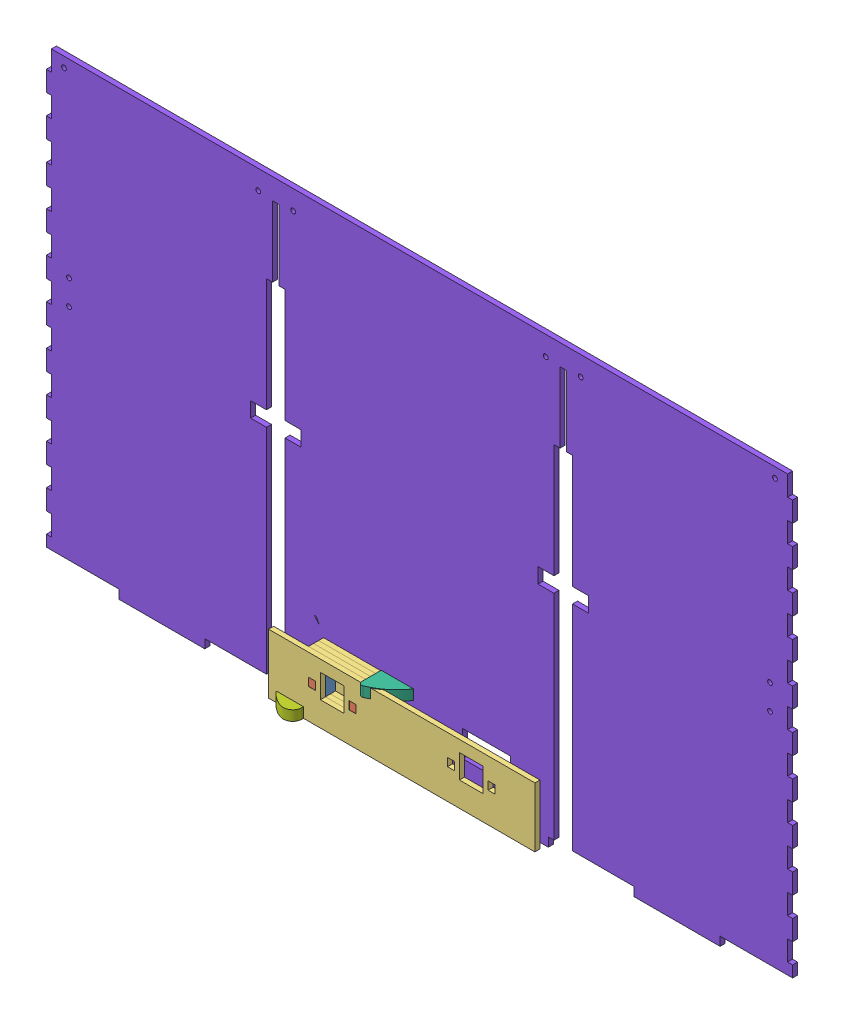
SolidWorks assembly extended nosepoke, configuration Default. Lengths in mm.
Overall size (470.79 279.4 46.18).
26 component instances, 8 part files, 60 mates.
Components (placement in the parent):
- inner floor-1: inner floor [Default] at (-20.7659 5.8025 34.2831) size (3.17 16.5 43)
- preferenceV2_dispenser_IRAssembly - Copy-2: preferenceV2_dispenser_IRAssembly - Copy [Default] at (-26.7909 7.3575 22.0081) x (1 0 0) z (0 -1 0) size (30.1 15.2 5)
  - sparkfunIR_LEDandCase-1: sparkfunIR_LEDandCase [2Pin] at (-11.0025 21.2786 44.4241) x (-1 0 0) z (0 0 -1) size (4.3 15.2 5)
    - sparkfunIR_casing-1: sparkfunIR_casing [Default] at (-40.6525 -5.8286 32.4491) x (1 0 0) z (0 0 -1) size (4.3 15.2 5)
  - sparkfunIR_LEDandCase-2: sparkfunIR_LEDandCase [3Pin] at (44.5025 21.2786 -20.4741) size (4.3 15.2 5)
    - sparkfunIR_casing-1: sparkfunIR_casing [Default] at (-40.6525 -5.8286 32.4491) x (1 0 0) z (0 0 -1) size (4.3 15.2 5)
- outside guard extended-1: outside guard extended [Default] at (9.7924 23.2146 37.4581) size (168 37.72 3.17)
- inner floor-2: inner floor [Default] at (-2.5909 5.8025 34.2831) size (3.17 16.5 43)
- outside guard extended-3: outside guard extended [second face] at (9.7974 23.2146 34.2831) size (36.35 37.72 3.17)
- outside guard extended-4: outside guard extended [second face] at (9.7974 23.2146 31.1081) size (36.35 37.72 3.17)
- outside guard extended-5: outside guard extended [back face] at (9.7974 23.2146 27.9331) size (36.35 37.72 3.17)
- nosepoke_cap-1: nosepoke_cap [Default] at (-25.7319 2.2657 -1.4169) size (36.45 15.97 23) (hidden)
- Part2^extended nosepoke-1: Part2^extended nosepoke [Default] at (9.7924 26.7946 21.5831) size (51.28 36.05 3.17) (hidden, virtual)
- side_guard_A-1: side_guard_A [Default] at (8.0751 11.9085 24.7581) x (1 0 0) z (0 0 -1) size (20.32 6.35 14.38) (hidden)
- side_guard_A-2: side_guard_A [Default] at (8.0751 5.5585 24.7581) x (1 0 0) z (0 0 -1) size (20.32 6.35 14.38) (hidden)
- side_guard_A-3: side_guard_A [Default] at (8.0751 -19.8415 24.7581) x (1 0 0) z (0 0 -1) size (20.32 6.35 14.38) (hidden)
- side_guard_A-4: side_guard_A [Default] at (8.0751 -0.7915 24.7581) x (1 0 0) z (0 0 -1) size (20.32 6.35 14.38) (hidden)
- side_guard_A-5: side_guard_A [Default] at (8.0751 -7.1415 24.7581) x (1 0 0) z (0 0 -1) size (20.32 6.35 14.38) (hidden)
- side_guard_A-6: side_guard_A [Default] at (8.0751 -13.4915 24.7581) x (1 0 0) z (0 0 -1) size (20.32 6.35 14.38) (hidden)
- side_guard_B-1: side_guard_B [Default] at (-49.4865 -19.8415 24.7581) x (1 0 0) z (0 0 -1) size (23.13 6.35 20.07) (hidden)
- side_guard_B-2: side_guard_B [Default] at (-49.4865 -0.7915 24.7581) x (1 0 0) z (0 0 -1) size (23.13 6.35 20.07) (hidden)
- side_guard_B-3: side_guard_B [Default] at (-49.4865 -7.1415 24.7581) x (1 0 0) z (0 0 -1) size (23.13 6.35 20.07) (hidden)
- side_guard_B-4: side_guard_B [Default] at (-49.4865 5.5585 24.7581) x (1 0 0) z (0 0 -1) size (23.13 6.35 20.07) (hidden)
- side_guard_B-5: side_guard_B [Default] at (-49.4865 11.9085 24.7581) x (1 0 0) z (0 0 -1) size (23.13 6.35 20.07) (hidden)
- side_guard_B-6: side_guard_B [Default] at (-49.4865 -13.4915 24.7581) x (1 0 0) z (0 0 -1) size (23.13 6.35 20.07) (hidden)
- preferenceV2_chamberFront_nosepokes_scoped-1: preferenceV2_chamberFront_nosepokes_scoped [front_nosepoke_scoped] at (32.2189 107.6367 21.5831) size (470.79 279.4 3.17)
Mates (geometry in assembly coordinates):
- Coincident35: coincident aligned: plane of outside guard extended-1 through (-28.2709 11.5258 -2.2013) normal (0 1 0); plane of outside guard extended-3 through (-28.2659 11.5258 -5.3763) normal (0 1 0)
- Coincident37: coincident aligned: plane of outside guard extended-3 through (-28.2659 11.5258 -5.3763) normal (0 1 0); plane of outside guard extended-4 through (-28.2659 11.5258 -8.5513) normal (0 1 0)
- Coincident38: coincident aligned: plane of outside guard extended-4 through (-28.2659 11.5258 -8.5513) normal (0 1 0); plane of outside guard extended-5 through (-28.2659 11.5258 -11.7263) normal (0 1 0)
- Coincident39: coincident aligned: plane of outside guard extended-4 through (8.0801 8.3508 27.9331) normal (1 0 0); plane of outside guard extended-5 through (8.0801 8.3508 24.7581) normal (1 0 0)
- Coincident40: coincident aligned: plane of outside guard extended-3 through (8.0801 8.3508 31.1081) normal (1 0 0); plane of outside guard extended-4 through (8.0801 8.3508 27.9331) normal (1 0 0)
- Coincident41: coincident: plane of outside guard extended-3 through (-25.0909 -10.6975 24.2831) normal (1 0 0); plane of outside guard extended-4 through (-25.0909 -10.6975 21.1081) normal (1 0 0)
- Coincident42: coincident: plane of outside guard extended-4 through (-25.0909 -10.6975 21.1081) normal (1 0 0); plane of outside guard extended-5 through (-25.0909 -10.6975 17.9331) normal (1 0 0)
- Coincident44: coincident: plane of outside guard extended-1 through (-25.0909 -5.6175 34.2831) normal (1 0 0); plane of outside guard extended-3 through (-25.0909 -10.6975 24.2831) normal (1 0 0)
- Coincident45: coincident: plane of outside guard extended-3 through (-25.0909 -10.6975 24.2831) normal (1 0 0); plane of outside guard extended-4 through (-25.0909 -10.6975 21.1081) normal (1 0 0)
- Coincident46: coincident: plane of outside guard extended-4 through (-25.0909 -10.6975 21.1081) normal (1 0 0); plane of outside guard extended-5 through (-25.0909 -10.6975 17.9331) normal (1 0 0)
- Coincident50: coincident anti-aligned: plane of outside guard extended-1 through (9.7924 23.2146 34.2831) normal (0 0 -1); plane of outside guard extended-3 through (9.7974 23.2146 34.2831) normal (0 0 1)
- Coincident51: coincident anti-aligned: plane of outside guard extended-3 through (9.7974 23.2146 31.1081) normal (0 0 -1); plane of outside guard extended-4 through (9.7974 23.2146 31.1081) normal (0 0 1)
- Coincident52: coincident anti-aligned: plane of outside guard extended-4 through (9.7974 23.2146 27.9331) normal (0 0 -1); plane of outside guard extended-5 through (9.7974 23.2146 27.9331) normal (0 0 1)
- Coincident53: coincident anti-aligned: plane of inner floor-1 through (-17.5909 5.8025 34.2831) normal (0 0 1); plane of outside guard extended-1 through (9.7924 23.2146 34.2831) normal (0 0 -1)
- Coincident55: coincident: plane of inner floor-1 through (-17.5909 -10.6975 34.2831) normal (0 -1 0); plane of outside guard extended-5 through (-28.2659 -10.6975 -11.7263) normal (0 1 0)
- Coincident56: coincident anti-aligned: plane of outside guard extended-1 through (9.7924 23.2146 34.2831) normal (0 0 -1); plane of inner floor-2 through (0.5841 5.8025 34.2831) normal (0 0 1)
- Coincident57: coincident: plane of inner floor-2 through (0.5841 -10.6975 34.2831) normal (0 -1 0); plane of outside guard extended-5 through (-28.2659 -10.6975 -11.7263) normal (0 1 0)
- Coincident59: coincident aligned: plane of preferenceV2_dispenser_IRAssembly - Copy-2/sparkfunIR_LEDandCase-1/sparkfunIR_casing-1 through (5.0091 -7.1175 37.4581) normal (0 0 1); plane of outside guard extended-1 through (9.7924 23.2146 37.4581) normal (0 0 1)
- Coincident60: coincident: plane of inner floor-2 through (-2.5909 5.8025 34.2831) normal (-1 0 0); plane of outside guard extended-5 through (-2.5909 4.3025 24.7581) normal (1 0 0)
- Coincident61: coincident: plane of inner floor-1 through (-17.5909 5.8025 34.2831) normal (1 0 0); plane of outside guard extended-5 through (-17.5909 4.3025 24.7581) normal (-1 0 0)
- Distance2: distance = 3.175 mm anti-aligned: plane of nosepoke_cap-1 through (-25.7319 2.2657 21.5831) normal (0 0 1); plane of outside guard extended-5 through (9.7974 23.2146 24.7581) normal (0 0 -1)
- Coincident67: coincident anti-aligned: plane of inner floor-2 through (0.5841 5.8025 34.2831) normal (0 1 0); plane of nosepoke_cap-1 through (-2.5909 5.8025 -19.2169) normal (0 -1 0)
- Coincident68: coincident anti-aligned: plane of inner floor-2 through (-2.5909 5.8025 34.2831) normal (-1 0 0); plane of nosepoke_cap-1 through (-2.5909 5.8025 -19.2169) normal (1 0 0)
- Coincident72: coincident anti-aligned: plane of outside guard extended-5 through (9.7974 23.2146 24.7581) normal (0 0 -1); plane of Part2^extended nosepoke-1 through (9.7924 26.7946 24.7581) normal (0 0 1)
- Coincident73: coincident anti-aligned: plane of preferenceV2_dispenser_IRAssembly - Copy-2/sparkfunIR_LEDandCase-2/sparkfunIR_casing-1 through (-22.9409 -7.1175 37.4581) normal (0 -1 0); plane of Part2^extended nosepoke-1 through (-25.0909 -7.1175 24.7581) normal (0 1 0)
- Coincident74: coincident anti-aligned: plane of preferenceV2_dispenser_IRAssembly - Copy-2/sparkfunIR_LEDandCase-2/sparkfunIR_casing-1 through (-25.0909 -2.1175 37.4581) normal (-1 0 0); plane of Part2^extended nosepoke-1 through (-25.0909 -7.1175 24.7581) normal (1 0 0)
- Coincident94: coincident aligned: plane of outside guard extended-5 through (9.7974 23.2146 24.7581) normal (0 0 -1); plane of side_guard_A-3 through (8.0751 -26.1915 24.7581) normal (0 0 -1)
- Coincident95: coincident aligned: plane of outside guard extended-1 through (-28.2709 -26.1915 -4.0938) normal (0 -1 0); plane of side_guard_A-3 through (-3.9794 -26.1915 2.7588) normal (0 -1 0)
- Coincident96: coincident: plane of outside guard extended-1 through (8.0751 8.3508 34.2831) normal (1 0 0); plane of side_guard_A-3 through (8.0751 -26.1915 24.7581) normal (-1 0 0)
- Coincident97: coincident anti-aligned: plane of side_guard_A-3 through (-3.9794 -19.8415 2.7588) normal (0 1 0); plane of side_guard_A-6 through (-3.9794 -19.8415 2.7588) normal (0 -1 0)
- Concentric7: concentric aligned: cylinder of side_guard_A-3 through (-3.9794 -26.1915 2.7588) axis (0 1 0) radius 39.1418; cylinder of side_guard_A-6 through (-3.9794 -19.8415 2.7588) axis (0 1 0) radius 39.1418
- Coincident98: coincident anti-aligned: plane of side_guard_A-5 through (-3.9794 -13.4915 2.7588) normal (0 -1 0); plane of side_guard_A-6 through (-3.9794 -13.4915 2.7588) normal (0 1 0)
- Concentric8: concentric aligned: cylinder of side_guard_A-5 through (-3.9794 -13.4915 2.7588) axis (0 1 0) radius 39.1418; cylinder of side_guard_A-6 through (-3.9794 -19.8415 2.7588) axis (0 1 0) radius 39.1418
- Coincident99: coincident anti-aligned: plane of side_guard_A-4 through (-3.9794 -7.1415 2.7588) normal (0 -1 0); plane of side_guard_A-5 through (-3.9794 -7.1415 2.7588) normal (0 1 0)
- Concentric9: concentric aligned: cylinder of side_guard_A-4 through (-3.9794 -7.1415 2.7588) axis (0 1 0) radius 39.1418; cylinder of side_guard_A-5 through (-3.9794 -13.4915 2.7588) axis (0 1 0) radius 39.1418
- Coincident100: coincident anti-aligned: plane of side_guard_A-2 through (-3.9794 -0.7915 2.7588) normal (0 -1 0); plane of side_guard_A-4 through (-3.9794 -0.7915 2.7588) normal (0 1 0)
- Coincident101: coincident anti-aligned: plane of side_guard_A-2 through (-3.9794 -0.7915 2.7588) normal (0 -1 0); plane of side_guard_A-4 through (-3.9794 -0.7915 2.7588) normal (0 1 0)
- Concentric10: concentric aligned: cylinder of side_guard_A-2 through (-3.9794 -0.7915 2.7588) axis (0 1 0) radius 39.1418; cylinder of side_guard_A-4 through (-3.9794 -7.1415 2.7588) axis (0 1 0) radius 39.1418
- Coincident102: coincident anti-aligned: plane of side_guard_A-1 through (-3.9794 5.5585 2.7588) normal (0 -1 0); plane of side_guard_A-2 through (-3.9794 5.5585 2.7588) normal (0 1 0)
- Concentric11: concentric aligned: cylinder of side_guard_A-1 through (-3.9794 5.5585 2.7588) axis (0 1 0) radius 39.1418; cylinder of side_guard_A-2 through (-3.9794 -0.7915 2.7588) axis (0 1 0) radius 39.1418
- Coincident103: coincident anti-aligned: plane of outside guard extended-4 through (-28.2659 8.3508 27.9331) normal (-1 0 0); plane of side_guard_B-1 through (-28.2659 -26.1915 24.7581) normal (1 0 0)
- Coincident104: coincident aligned: plane of outside guard extended-5 through (9.7974 23.2146 24.7581) normal (0 0 -1); plane of side_guard_B-1 through (-49.4865 -26.1915 24.7581) normal (0 0 -1)
- Coincident105: coincident aligned: plane of outside guard extended-5 through (-28.2659 -26.1915 -13.6188) normal (0 -1 0); plane of side_guard_B-1 through (-42.4162 -26.1915 40.4723) normal (0 -1 0)
- Coincident106: coincident anti-aligned: plane of side_guard_B-1 through (-42.4162 -19.8415 40.4723) normal (0 1 0); plane of side_guard_B-6 through (-42.4162 -19.8415 40.4723) normal (0 -1 0)
- Coincident107: coincident aligned: plane of side_guard_B-1 through (-49.4865 -26.1915 24.7581) normal (0 0 -1); plane of side_guard_B-6 through (-49.4865 -19.8415 24.7581) normal (0 0 -1)
- Coincident108: coincident anti-aligned: plane of outside guard extended-4 through (-28.2659 8.3508 27.9331) normal (-1 0 0); plane of side_guard_B-6 through (-28.2659 -19.8415 24.7581) normal (1 0 0)
- Coincident109: coincident anti-aligned: plane of side_guard_B-3 through (-42.4162 -13.4915 40.4723) normal (0 -1 0); plane of side_guard_B-6 through (-42.4162 -13.4915 40.4723) normal (0 1 0)
- Coincident110: coincident: line of outside guard extended-4 through (-28.2659 11.5258 27.9331) axis (0 -1 0); plane of side_guard_B-3 through (-28.2659 -13.4915 24.7581) normal (1 0 0)
- Coincident111: coincident aligned: plane of side_guard_B-3 through (-49.4865 -13.4915 24.7581) normal (0 0 -1); plane of side_guard_B-6 through (-49.4865 -19.8415 24.7581) normal (0 0 -1)
- Coincident112: coincident anti-aligned: plane of side_guard_B-2 through (-42.4162 -7.1415 40.4723) normal (0 -1 0); plane of side_guard_B-3 through (-42.4162 -7.1415 40.4723) normal (0 1 0)
- Coincident113: coincident aligned: plane of side_guard_B-2 through (-49.4865 -7.1415 24.7581) normal (0 0 -1); plane of side_guard_B-3 through (-49.4865 -13.4915 24.7581) normal (0 0 -1)
- Coincident114: coincident anti-aligned: plane of outside guard extended-4 through (-28.2659 8.3508 27.9331) normal (-1 0 0); plane of side_guard_B-2 through (-28.2659 -7.1415 24.7581) normal (1 0 0)
- Coincident115: coincident aligned: plane of side_guard_B-2 through (-49.4865 -7.1415 24.7581) normal (0 0 -1); plane of side_guard_B-4 through (-49.4865 -0.7915 24.7581) normal (0 0 -1)
- Coincident116: coincident anti-aligned: plane of side_guard_B-2 through (-42.4162 -0.7915 40.4723) normal (0 1 0); plane of side_guard_B-4 through (-42.4162 -0.7915 40.4723) normal (0 -1 0)
- Coincident117: coincident anti-aligned: plane of outside guard extended-4 through (-28.2659 8.3508 27.9331) normal (-1 0 0); plane of side_guard_B-4 through (-28.2659 -0.7915 24.7581) normal (1 0 0)
- Coincident118: coincident anti-aligned: plane of side_guard_B-4 through (-42.4162 5.5585 40.4723) normal (0 1 0); plane of side_guard_B-5 through (-42.4162 5.5585 40.4723) normal (0 -1 0)
- Coincident119: coincident anti-aligned: plane of outside guard extended-4 through (-28.2659 8.3508 27.9331) normal (-1 0 0); plane of side_guard_B-5 through (-28.2659 5.5585 24.7581) normal (1 0 0)
- Coincident120: coincident aligned: plane of side_guard_B-4 through (-49.4865 -0.7915 24.7581) normal (0 0 -1); plane of side_guard_B-5 through (-49.4865 5.5585 24.7581) normal (0 0 -1)
- Coincident121: coincident anti-aligned: plane of preferenceV2_dispenser_IRAssembly - Copy-2/sparkfunIR_LEDandCase-2/sparkfunIR_casing-1 through (-22.9409 -2.1175 37.4581) normal (0 1 0); plane of outside guard extended-1 through (-25.0929 -2.1175 34.2831) normal (0 -1 0)
- Coincident122: coincident anti-aligned: plane of outside guard extended-5 through (9.7974 23.2146 24.7581) normal (0 0 -1); plane of preferenceV2_chamberFront_nosepokes_scoped-1 through (32.2189 107.6367 24.7581) normal (0 0 1)
